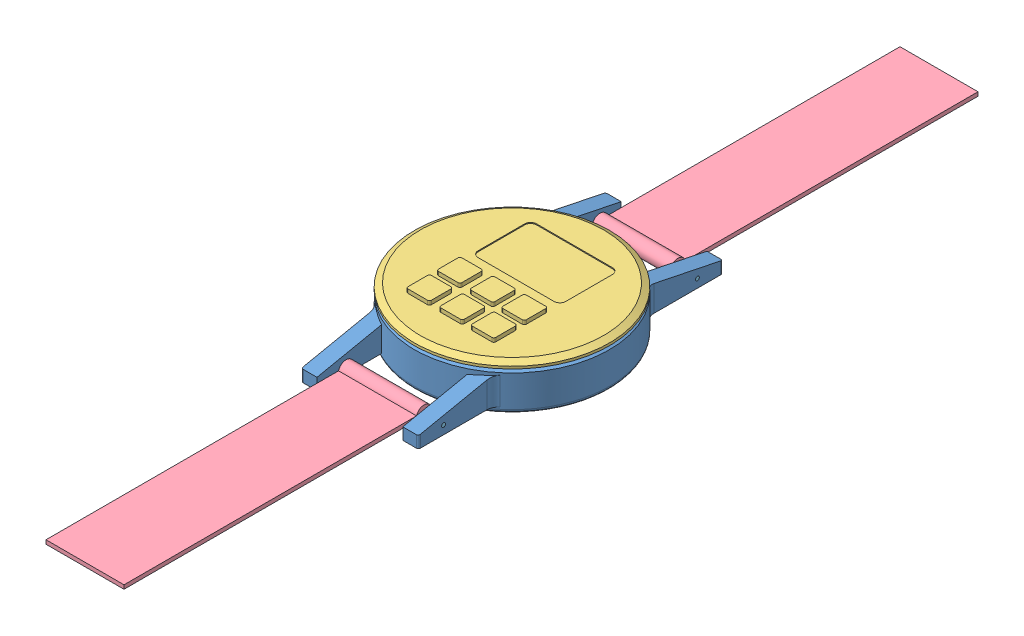
SolidWorks assembly Assembly, configuration Default. Lengths in mm.
Overall size (100 30.41 437.87).
7 component instances, 5 part files, 13 mates.
Components (placement in the parent):
- AgroBand-1: AgroBand [Default] at (70.3493 87.9708 115.6846) size (100 20 156)
- PCB-1: PCB [Default] at (70.3493 77.9708 115.6846) size (84 25.41 84)
- Screen-1: Screen [Default] at (70.3493 87.9708 115.6846) size (100 5 100)
- Strap-1: Strap [Default] at (70.3493 75.3 27.7764) size (40 8 157.87)
- Strap PIn-1: Strap PIn [Default] at (70.3493 75.3 50.6217) size (60 2 2)
- Strap-2: Strap [Default] at (70.3493 75.3 203.5927) x (1 0 0) z (0 0 -1) size (40 8 157.87)
- Strap PIn-2: Strap PIn [Default] at (70.3493 75.3 180.7474) size (60 2 2)
Mates (geometry in assembly coordinates):
- Coincident1: coincident: plane of ? through (70.3493 77.9708 115.6846) normal (0 1 0); plane of PCB-1 through (70.3493 77.9708 115.6846) normal (0 -1 0)
- Concentric1: concentric: cylinder of ? through (70.3493 77.9708 115.6846) axis (0 1 0) radius 42; cylinder of PCB-1 through (70.3493 79.9708 115.6846) axis (0 -1 0) radius 42
- Coincident2: coincident: plane of ? through (70.3493 87.9708 115.6846) normal (0 1 0); plane of ? through (70.3493 87.9708 115.6846) normal (0 -1 0)
- Concentric2: concentric: cylinder of ? through (70.3493 67.9708 115.6846) axis (0 1 0) radius 50; cylinder of ? through (70.3493 90.9708 115.6846) axis (0 -1 0) radius 50
- Concentric3: concentric: cylinder of ? through (125.3493 75.3 50.6217) axis (-1 0 0) radius 1; cylinder of Strap PIn-1 through (40.3493 75.3 50.6217) axis (1 0 0) radius 1
- Coincident3: coincident: plane of ? through (100.3493 87.9708 115.6846) normal (1 0 0); plane of Strap PIn-1 through (100.3493 75.3 50.6217) normal (1 0 0)
- Concentric4: concentric: cylinder of assembly; cylinder of assembly; cylinder of Strap-1 through (50.3493 75.3 50.6217) axis (1 0 0) radius 1; cylinder of Strap PIn-1 through (40.3493 75.3 50.6217) axis (1 0 0) radius 1
- Distance1: distance = 2 mm: plane of Strap-1 through (90.3493 75.3 27.7764) normal (1 0 0); plane of ? through (92.3493 57.9708 37.6846) normal (-1 0 0)
- Concentric5: concentric: cylinder of ? through (120.3493 75.3 180.7474) axis (-1 0 0) radius 1; cylinder of Strap PIn-2 through (40.3493 75.3 180.7474) axis (1 0 0) radius 1
- Coincident5: coincident: plane of ? through (100.3493 87.9708 115.6846) normal (1 0 0); plane of Strap PIn-2 through (100.3493 75.3 180.7474) normal (1 0 0)
- Concentric6: concentric: cylinder of assembly; cylinder of assembly; cylinder of Strap-2 through (50.3493 75.3 180.7474) axis (1 0 0) radius 1; cylinder of Strap PIn-2 through (40.3493 75.3 180.7474) axis (1 0 0) radius 1
- Distance2: distance = 2 mm: plane of Strap-2 through (90.3493 75.3 203.5927) normal (1 0 0); plane of ? through (92.3493 57.9708 193.6846) normal (-1 0 0)
- Coincident7: coincident: plane of assembly; plane of assembly; plane of Strap-1 through (50.3493 76.3 27.7764) normal (0 1 0); plane of Strap-2 through (50.3493 76.3 203.5927) normal (0 1 0)
